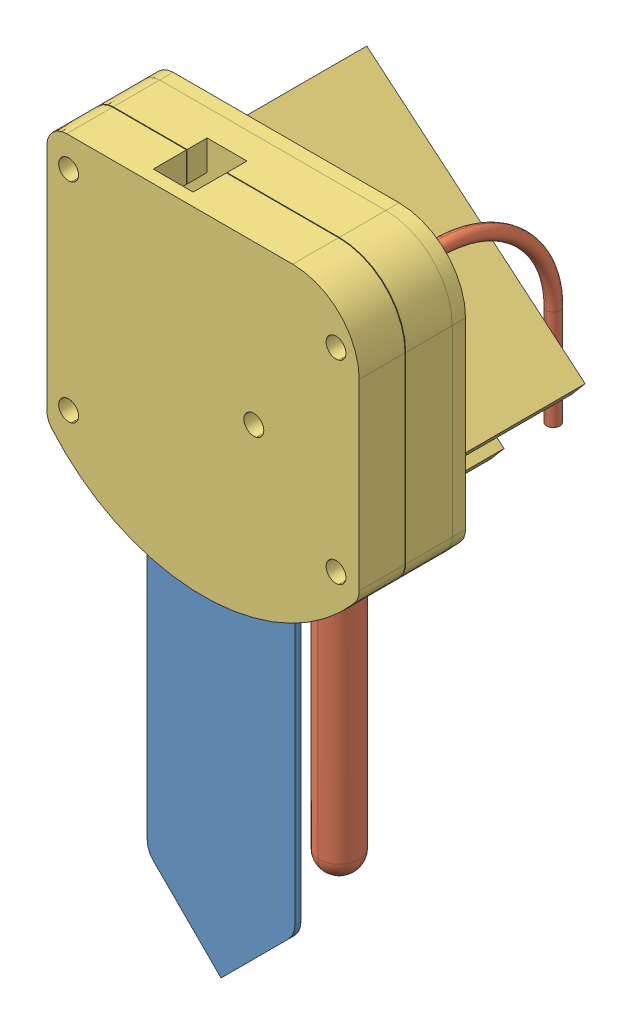
SolidWorks assembly Sensors, configuration Default. Lengths in mm.
Overall size (47 107.5 38.24).
3 component instances, 3 part files, 5 mates.
Components (placement in the parent):
- Capacative Soil Moisture Sensor v1.2-1: Capacative Soil Moisture Sensor v1.2 [Default] at (-71.3915 55.8246 29.9167) size (22.23 100 9.2)
- ds18b20-1: ds18b20 [Default] at (-51.504 8.3534 32.9167) x (0.076434 0 -0.997075) z (0 -1 0) size (34.1 6 75.95)
- sensor casing-1: sensor casing [Default] at (-71.3915 55.8246 29.9167) x (-1 0 0) z (0 0 -1) size (47 50 34)
Mates (geometry in assembly coordinates):
- InPlace1: in place: plane of Capacative Soil Moisture Sensor v1.2-1 through (-79.329 -29.2478 29.9167) normal (0 0 -1); plane of ? through (0 0 29.9167) normal (0 0 -1); moOrthogonalPlaneRef_w of Capacative Soil Moisture Sensor v1.2-1 through (-79.329 -29.2478 29.9167) normal (0 0 -1); plane of ? through (0 0 29.9167) normal (0 1 0); plane of Capacative Soil Moisture Sensor v1.2-1 through (-79.329 -29.2478 29.9167) normal (0 0 -1); plane of ? through (0 0 29.9167) normal (-1 0 0); plane of Capacative Soil Moisture Sensor v1.2-1 through (-79.329 -29.2478 29.9167) normal (0 0 -1); unknown of sensor casing-1
- Coincident1: coincident aligned: plane of ?; plane of ?
- Coincident2: coincident aligned: moOrthogonalPlaneRef_w of Capacative Soil Moisture Sensor v1.2-1 through (-71.3915 55.8246 29.9167) normal (0 1 0); plane of Part19^Assem8-1 through (-71.3915 55.8246 29.9167) normal (0 1 0)
- Coincident3: coincident anti-aligned: moOrthogonalPlaneRef_w of Capacative Soil Moisture Sensor v1.2-1 through (-71.3915 55.8246 29.9167) normal (1 0 0); plane of Part19^Assem8-1 through (-71.3915 55.8246 29.9167) normal (-1 0 0)
- Concentric1: concentric aligned: cylinder of ds18b20-1 through (-51.504 -16.6466 32.9167) axis (0 -1 0) radius 3; cylinder of Part19^Assem8-1 through (-51.504 49.8246 32.9167) axis (0 -1 0) radius 3.25
